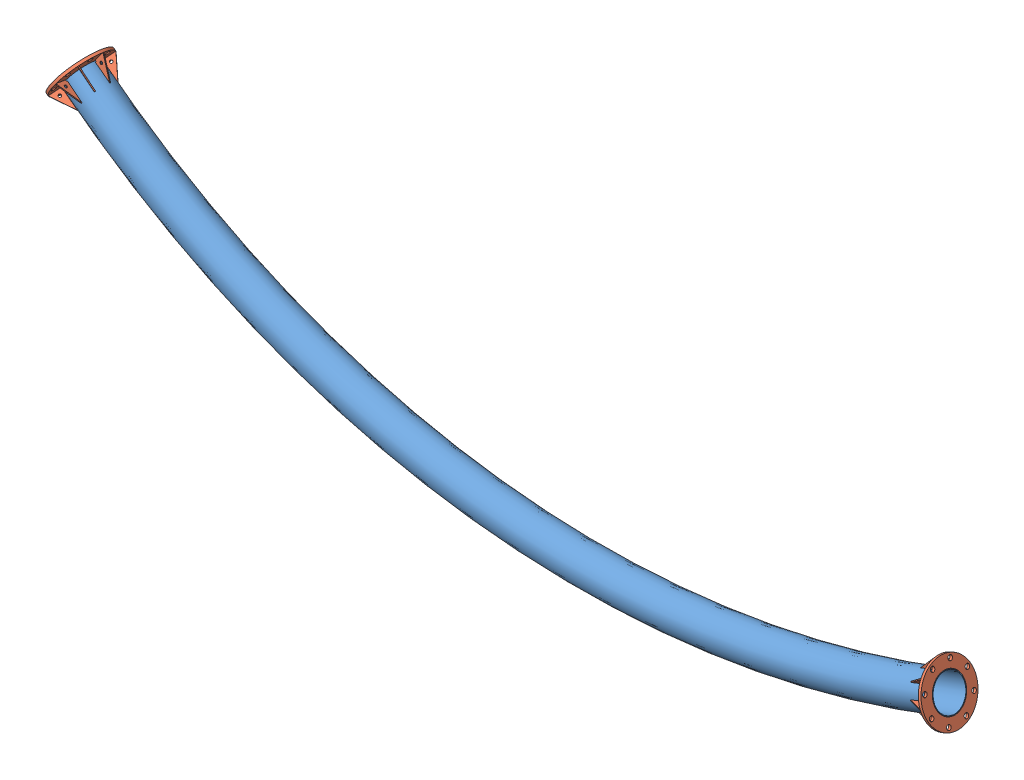
SolidWorks assembly pipe_b_asm, configuration Default. Lengths in mm.
Overall size (4385.26 995.26 375.05).
3 component instances, 2 part files, 3 mates.
Components (placement in the parent):
- pipe_b^pipe_b_asm-1: pipe_b^pipe_b_asm [Default<As Machined>] at origin size (4298.5 932.26 243.24) (virtual)
- pipe_flange-1: pipe_flange [Default] at (1016.6393 -3466.0879 3799.6778) x (-0.523817 -0.829584 -0.193404) z (0.836546 -0.543801 0.066861) size (279.4 279.4 111.05)
- pipe_flange-2: pipe_flange [Default] at (5240.5926 -3970.6698 3800.0944) x (0.191748 -0.360818 0.912712) z (-0.941114 -0.331447 0.066685) size (279.4 279.4 111.05)
Mates (geometry in assembly coordinates):
- Concentric1: concentric anti-aligned: circle of pipe_flange-1; circle of pipe_b^pipe_b_asm-1
- Coincident1: coincident aligned: circle of pipe_b^pipe_b_asm-1; plane of pipe_flange-1 through (1016.6393 -3466.0879 3799.6778) normal (-0.836546 0.543801 -0.066861)
- Coincident2: coincident aligned: plane of pipe_flange-2 through (5240.5926 -3970.6698 3800.0944) normal (0.941114 0.331447 -0.066685); plane of pipe_b^pipe_b_asm-1 through (5240.5926 -3970.6698 3800.0944) normal (0.941114 0.331447 -0.066685)
